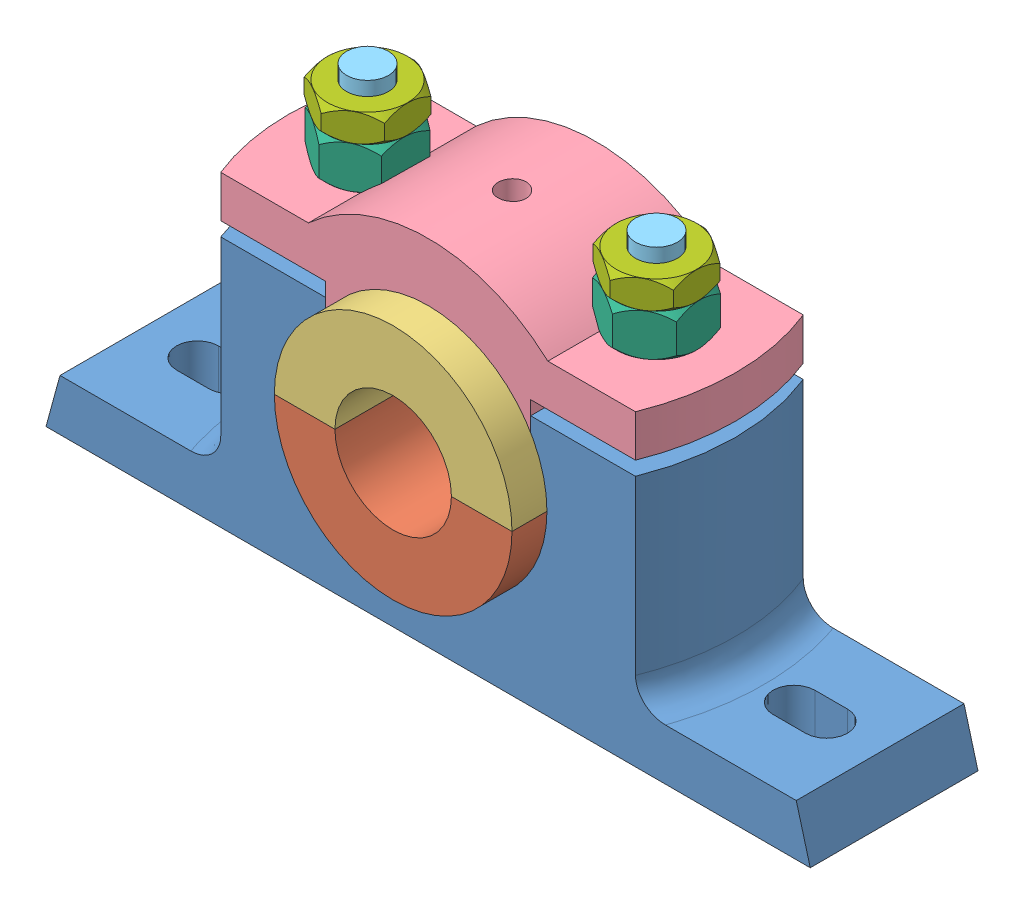
SolidWorks assembly Assem1, configuration Default. Lengths in mm.
Overall size (4165.6 2133.6 1295.4).
10 component instances, 7 part files, 14 mates.
Components (placement in the parent):
- Casting-1: Casting [Default] at (1275.9722 1763.2915 3157.6412) size (4165.6 1371.6 914.4)
- brass 1-1: brass 1 [Default] at (1275.9722 2728.4915 3805.3412) x (0 -1 0) z (-1 0 0) size (647.7 1295.4 1295.4)
- brasse 2-1: brasse 2 [Default] at (1275.9722 2728.4915 2509.9412) x (0 1 0) z (-1 0 0) size (647.7 1295.4 1295.4)
- Cap-1: Cap [Default] at (1275.9722 2728.4915 3157.6412) size (2438.4 812.8 914.4)
- bolts-1: bolts [Default] at (488.5722 1966.4915 3157.6412) x (0 1 0) z (0 0 1) size (2082.8 482.6 482.6)
- nut 1-1: nut 1 [Default] at (488.5722 3553.9915 3157.6412) x (0.54179 0 -0.840514) z (0 -1 0) size (438.15 556.44 228.6)
- nut 3-1: nut 3 [Default] at (488.5722 3744.4915 3157.6412) x (1 0 0) z (0 -1 0) size (438.15 556.44 152.4)
- nut 3-2: nut 3 [Default] at (2063.3722 3744.4915 3157.6412) x (-1 0 0) z (0 1 0) size (438.15 556.44 152.4)
- nut 1-2: nut 1 [Default] at (2063.3722 3553.9915 3157.6412) x (-0.54179 0 -0.840514) z (0 1 0) size (438.15 556.44 228.6)
- bolts-2: bolts [Default] at (2063.3722 1966.4915 3157.6412) x (0 1 0) z (0 0 -1) size (2082.8 482.6 482.6)
Mates (geometry in assembly coordinates):
- Concentric1: concentric anti-aligned: cylinder of Casting-1 through (1275.9722 2728.4915 3614.8412) axis (0 0 -1) radius 482.6; cylinder of brass 1-1 through (1275.9722 2728.4915 3805.3412) axis (0 0 1) radius 482.6
- Concentric2: concentric anti-aligned: cylinder of Casting-1 through (1275.9722 2728.4915 3614.8412) axis (0 0 -1) radius 482.6; cylinder of brass 1-1 through (1275.9722 2728.4915 3805.3412) axis (0 0 1) radius 482.6
- Concentric3: concentric anti-aligned: cylinder of Casting-1 through (1275.9722 2245.8915 3157.6412) axis (0 1 0) radius 76.2; cylinder of brass 1-1 through (1275.9722 502728.4915 3157.6412) axis (0 -1 0) radius 76.2
- Concentric6: concentric anti-aligned: cylinder of brass 1-1 through (1275.9722 2728.4915 3805.3412) axis (0 0 -1) radius 317.5; cylinder of brasse 2-1 through (1275.9722 2728.4915 2509.9412) axis (0 0 1) radius 317.5
- Coincident5: coincident aligned: plane of brass 1-1 through (1593.4722 2728.4915 3805.3412) normal (0 0 1); plane of brasse 2-1 through (1593.4722 2728.4915 3805.3412) normal (0 0 1)
- Coincident6: coincident anti-aligned: plane of brass 1-1 through (1275.9722 2728.4915 3805.3412) normal (0 1 0); plane of brasse 2-1 through (1275.9722 2728.4915 2509.9412) normal (0 -1 0)
- Concentric8: concentric anti-aligned: cylinder of Casting-1 through (2063.3722 1966.4915 3157.6412) axis (0 -1 0) radius 114.3; cylinder of Cap-1 through (2063.3722 3439.6915 3157.6412) axis (0 1 0) radius 114.3
- Concentric11: concentric aligned: cylinder of Casting-1 through (488.5722 1966.4915 3157.6412) axis (0 -1 0) radius 114.3; cylinder of bolts-1 through (488.5722 3896.8915 3157.6412) axis (0 -1 0) radius 114.3
- Coincident10: coincident anti-aligned: plane of Casting-1 through (1275.9722 1966.4915 3157.6412) normal (0 -1 0); plane of bolts-1 through (488.5722 1966.4915 3157.6412) normal (0 1 0)
- Concentric14: concentric anti-aligned: cylinder of bolts-1 through (488.5722 3896.8915 3157.6412) axis (0 -1 0) radius 114.3; cylinder of nut 1-1 through (488.5722 3439.6915 3157.6412) axis (0 1 0) radius 114.3
- Concentric20: concentric anti-aligned: cylinder of bolts-1 through (488.5722 3896.8915 3157.6412) axis (0 -1 0) radius 114.3; cylinder of nut 3-1 through (488.5722 3668.2915 3157.6412) axis (0 1 0) radius 114.3
- Concentric22: concentric aligned: cylinder of brasse 2-1 through (1275.9722 2728.4915 2509.9412) axis (0 0 -1) radius 444.5; cylinder of Cap-1 through (1275.9722 2728.4915 3614.8412) axis (0 0 -1) radius 482.6
- Coincident15: coincident anti-aligned: plane of Cap-1 through (5.9722 3439.6915 3614.8412) normal (0 1 0); plane of nut 1-1 through (488.5722 3439.6915 3157.6412) normal (0 -1 0)
- Coincident16: coincident anti-aligned: plane of nut 1-1 through (488.5722 3668.2915 3157.6412) normal (0 1 0); plane of nut 3-1 through (488.5722 3668.2915 3157.6412) normal (0 -1 0)
